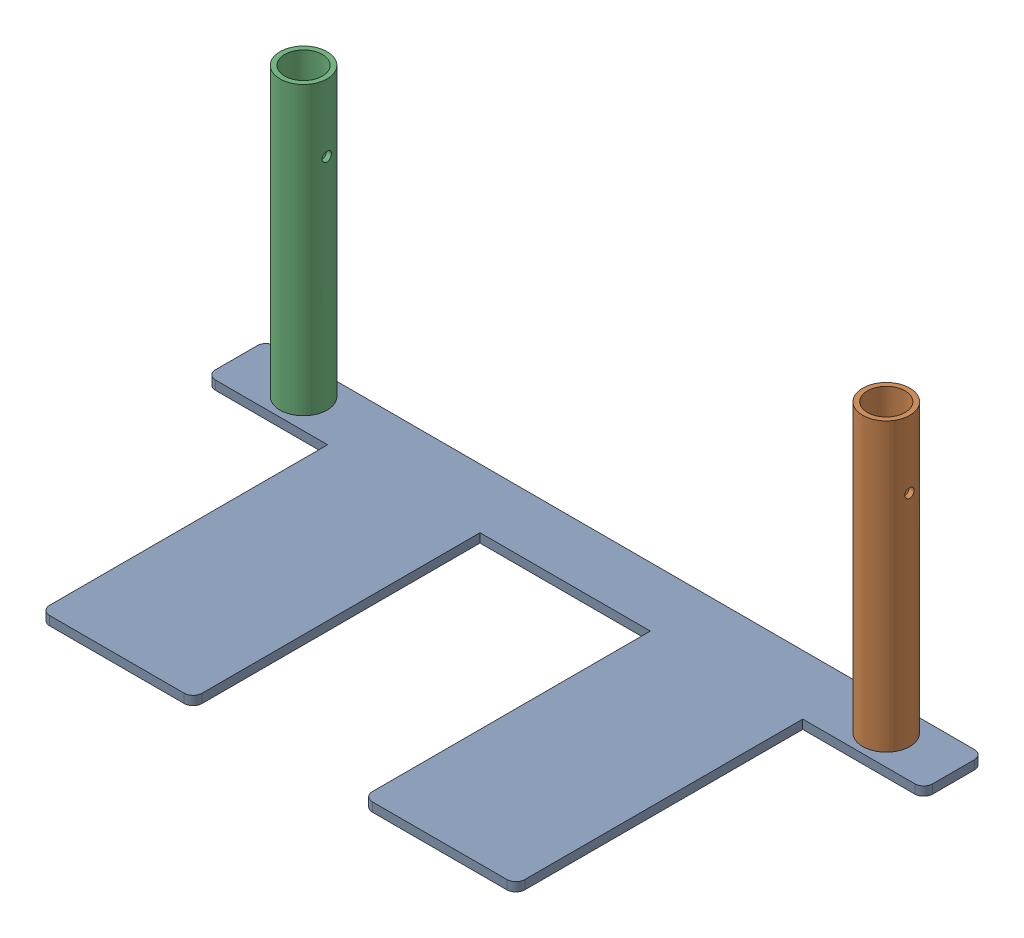
SolidWorks assembly GE-15022_ASM, configuration Default. Lengths in mm.
Overall size (508 209.55 245.36).
3 component instances, 2 part files, 0 mates.
Components (placement in the parent):
- GE-15022_01-1: GE-15022_01 [Default] at origin size (508 6.35 245.36)
- GE-15022_02-1: GE-15022_02 [Default] at (206.375 6.35 0) size (33.4 203.2 33.4)
- GE-15022_02-2: GE-15022_02 [Default] at (-206.375 6.35 0) size (33.4 203.2 33.4)
